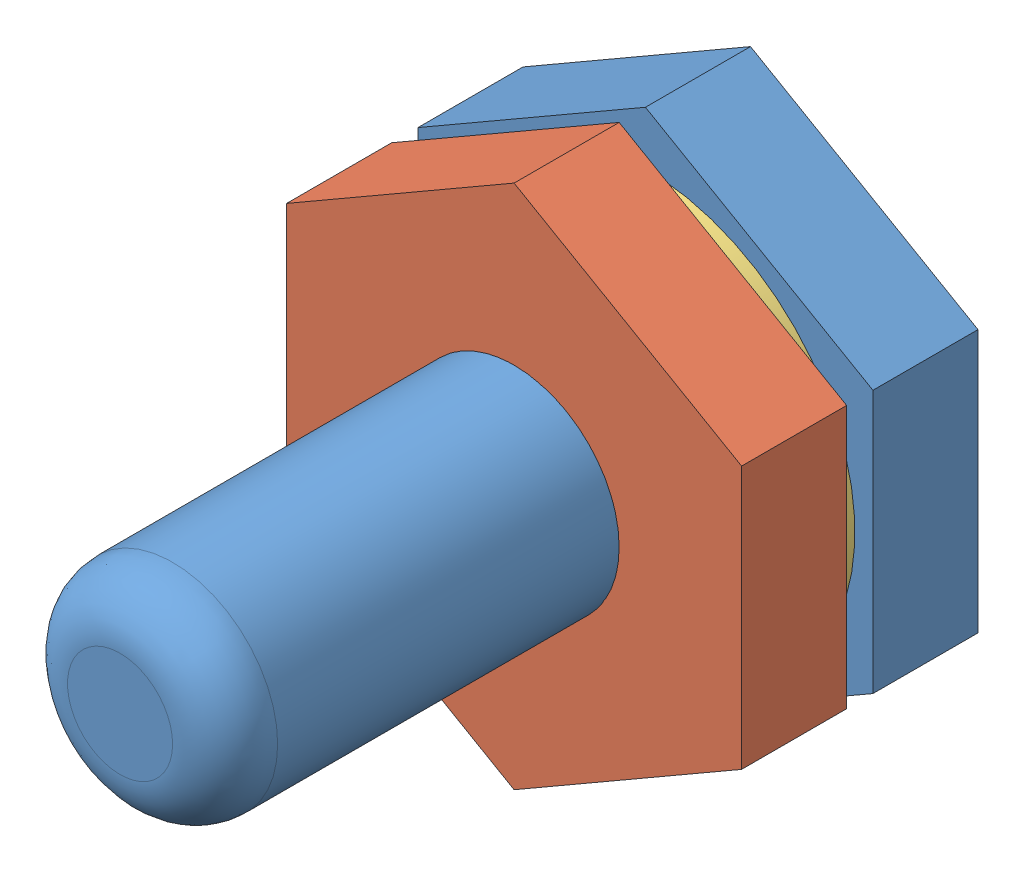
SolidWorks assembly Assem3, configuration Default. Lengths in mm.
Overall size (25.49 24.71 24).
3 component instances, 3 part files, 7 mates.
Components (placement in the parent):
- bolt-1: bolt [Default] at (23.095 9.2663 13.176) size (17.32 20 24)
- nut-1: nut [Default] at (19.3266 11.4117 18.176) x (0.919581 -0.3929 0) z (0 0 1) size (19.86 18.39 4)
- washer-1: washer [Default] at (33.5392 48.1017 17.176) x (0.026249 0.999655 0) z (0 0 1) size (16 16 1)
Mates (geometry in assembly coordinates):
- Parallel1: parallel anti-aligned: plane of bolt-1 through (23.095 9.2663 17.176) normal (0 0 1); plane of washer-1 through (14.0554 17.4307 17.176) normal (0 0 -1)
- Tangent5: tangent: torus of bolt-1; plane of washer-1 through (14.0554 17.4307 17.176) normal (0 0 -1)
- Parallel2: parallel aligned: plane of bolt-1 through (22.7419 22.456 17.176) normal (0.5 0.866025 0); plane of nut-1 through (22.7419 22.456 22.176) normal (0.5 0.866025 0)
- Parallel3: parallel aligned: plane of bolt-1 through (22.7419 12.456 17.176) normal (1 0 0); plane of nut-1 through (22.7419 12.456 22.176) normal (1 0 0)
- Concentric1: concentric anti-aligned: cylinder of bolt-1 through (14.0817 17.456 37.176) axis (0 0 -1) radius 4; cylinder of nut-1 through (14.0817 17.456 18.176) axis (0 0 1) radius 4
- Coincident4: coincident anti-aligned: plane of nut-1 through (19.3266 11.4117 18.176) normal (0 0 -1); plane of washer-1 through (14.0554 17.4307 18.176) normal (0 0 1)
- Coincident6: coincident: plane of bolt-1 through (23.095 9.2663 17.176) normal (0 0 1); plane of washer-1 through (14.0554 17.4307 17.176) normal (0 0 -1)
